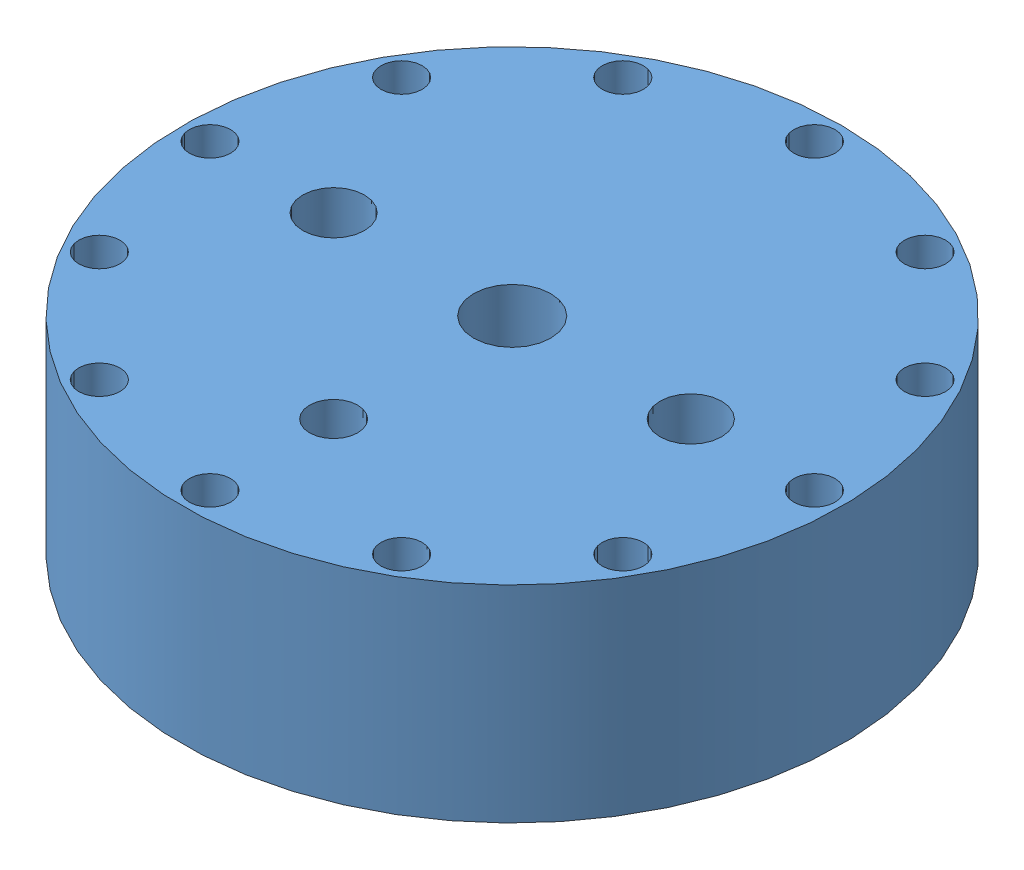
SolidWorks assembly impinging mu 1.0, configuration Default. Lengths in mm.
Overall size (152.4 50.81 152.4).
2 component instances, 2 part files, 4 mates.
Components (placement in the parent):
- impinging dome mu test 1.0-1: impinging dome mu test 1.0 [Default] at origin size (152.4 47.64 152.4)
- impinging injector plate mu test 1.0-1: impinging injector plate mu test 1.0 [Default] at (0 -47.6377 0) size (114.3 22.23 114.3)
Mates (geometry in assembly coordinates):
- Coincident1: coordinate: point of impinging dome mu test 1.0-1
- Concentric1: concentric anti-aligned: cylinder of impinging dome mu test 1.0-1 through (0 -15.8877 0) axis (0 -1 0) radius 76.2; cylinder of impinging injector plate mu test 1.0-1 through (0 -28.5877 0) axis (0 1 0) radius 57.15
- Coincident2: coincident aligned: plane of impinging dome mu test 1.0-1 through (-76.2 -47.6377 0) normal (0 -1 0); plane of impinging injector plate mu test 1.0-1 through (-55.7149 -47.6377 0) normal (0 -1 0)
- Coincident3: coincident aligned: plane of impinging injector plate mu test 1.0-1 through (0 -47.6377 0) normal (0 0 1)
